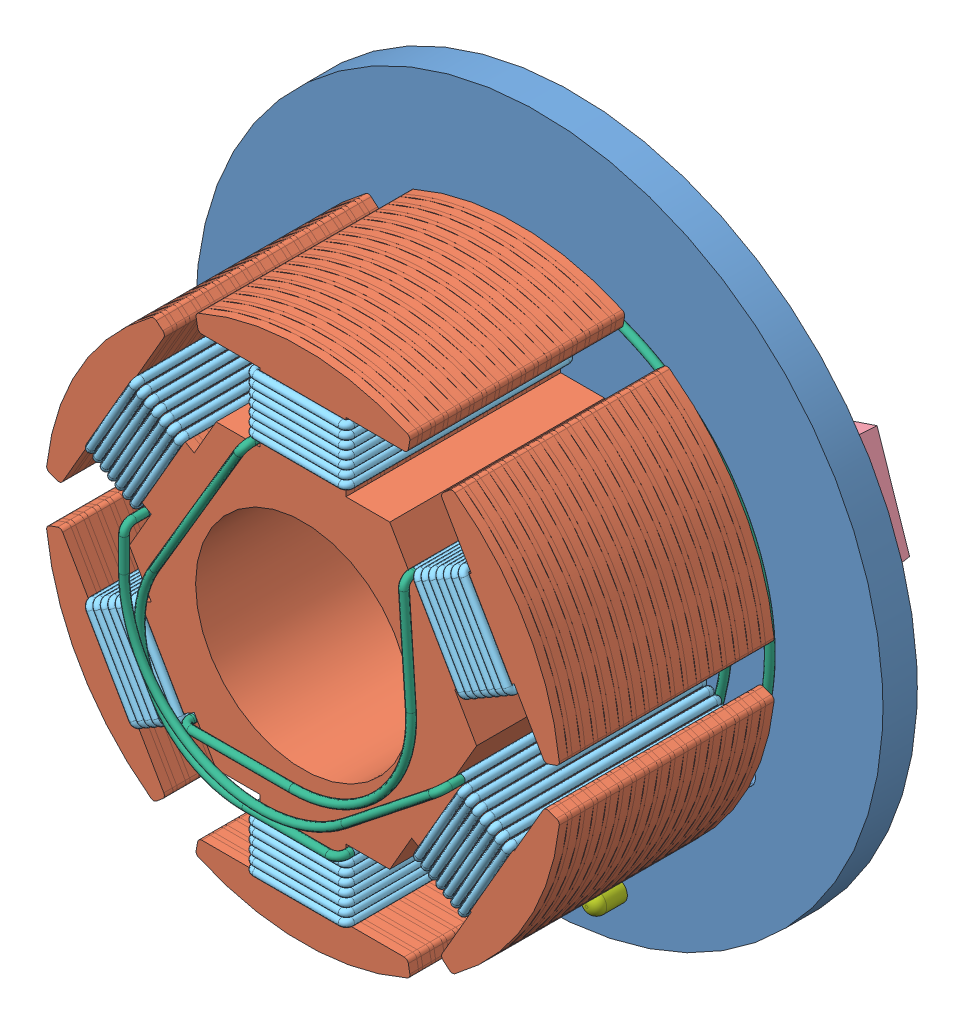
SolidWorks assembly Brushless motor, configuration Predeterminado. Lengths in mm.
Overall size (16 16 8.48).
12 component instances, 7 part files, 21 mates.
Components (placement in the parent):
- Board-1: Board [Predeterminado] at origin size (16 16 0.8)
- Stator-1: Stator [Predeterminado] at (0 0 3.55) size (11.93 12 5.5)
- Hall Effect sensor-1: Hall Effect sensor [WE] at (-5.3023 -0.9391 0) x (-0.233503 0.972356 0) z (-0.972356 -0.233503 0) size (6.3 1.6 2.6)
- Controller-1: Controller [Predeterminado] at (5.1574 2.3195 0) x (0.319288 -0.947658 0) z (0.947658 0.319288 0) size (4.81 0.99 3)
- Coil-1: Coil [Predeterminado] at (0 -5.01 1.29) x (-1 0 0) z (0 1 0) size (2.38 5.38 1.58)
- Pieza2^Brushless motor-1: Pieza2^Brushless motor [Predeterminado] at origin size (10.72 12.51 6.88) (virtual)
- Pieza3^Brushless motor-1: Pieza3^Brushless motor [Predeterminado] at (0 0 0.8) size (4.1 0.74 1.7) (virtual)
- Coil-2: Coil [Predeterminado] at (-4.3388 -2.505 1.29) x (-0.5 0.866025 0) z (0.866025 0.5 0) size (2.38 5.38 1.58)
- Coil-3: Coil [Predeterminado] at (-4.3388 2.505 1.29) x (0.5 0.866025 0) z (0.866025 -0.5 0) size (2.38 5.38 1.58)
- Coil-4: Coil [Predeterminado] at (0 5.01 1.29) x (1 0 0) z (0 -1 0) size (2.38 5.38 1.58)
- Coil-5: Coil [Predeterminado] at (4.3388 2.505 1.29) x (0.5 -0.866025 0) z (-0.866025 -0.5 0) size (2.38 5.38 1.58)
- Coil-6: Coil [Predeterminado] at (4.3388 -2.505 1.29) x (-0.5 -0.866025 0) z (-0.866025 0.5 0) size (2.38 5.38 1.58)
Mates (geometry in assembly coordinates):
- Coincidente1: coincident aligned: plane of Board-1 through (0 0 0) normal (0 0 1)
- Coincidente2: coincident aligned: plane of Board-1 through (0 0 0) normal (0 1 0)
- Coincidente3: coincident aligned: plane of Board-1 through (0 0 0) normal (1 0 0)
- Coincidente4: coincident anti-aligned: plane of Board-1 through (0 0 0.8) normal (0 0 1); plane of Stator-1 through (0 0 0.8) normal (0 0 -1)
- Concéntrica1: concentric aligned: cylinder of Board-1 through (0 0 0.8) axis (0 0 -1) radius 2.5; cylinder of Stator-1 through (0 0 6.3) axis (0 0 -1) radius 2.5
- Bloquear1: lock: unknown of Board-1; unknown of Hall Effect sensor-1
- Coincidente16: coincident anti-aligned: plane of Board-1 through (0 0 0) normal (0 0 -1); plane of Controller-1 through (5.1574 2.3195 0) normal (0 0 1)
- Bloquear2: lock: unknown of Board-1; unknown of Controller-1
- Coincidente17: coincident anti-aligned: plane of Coil-1 through (0 -5.01 1.29) normal (-1 0 0)
- Tangente1: tangent anti-aligned: plane of Stator-1 through (0 0 6.3) normal (0 0 1); cylinder of Coil-1 through (1 -5.01 6.39) axis (-1 0 0) radius 0.09
- Paralelo1: parallel aligned: plane of Coil-1 through (0 -5.01 1.29) normal (0 0 1)
- Tangente2: tangent anti-aligned: plane of Stator-1 through (2.3536 -5.1 6.1) normal (0 1 0); cylinder of Coil-1 through (1.1 -5.01 3.79) axis (0 0 1) radius 0.09
- Bloquear3: lock: unknown of Board-1; unknown of Coil-1
- EnPosición1: in place: plane of ? through (0 0 0) normal (0 0 1); moOrthogonalPlaneRef_w of ? through (0 0 0) normal (0 1 0); plane of ? through (0 0 0) normal (1 0 0); unknown of ?
- Coincidente18: coincident aligned: 
- Coincidente19: coincident aligned: plane of Pieza2^Brushless motor-1 through (0 0 0) normal (0 1 0)
- Coincidente20: coincident anti-aligned: plane of Pieza2^Brushless motor-1 through (0 0 0) normal (1 0 0)
- EnPosición2: in place: plane of ? through (0 0 0.8) normal (0 0 1); plane of Pieza3^Brushless motor-1 through (0 0 0.8) normal (0 0 1); plane of ? through (0 0 0.8) normal (0 0 1); plane of Pieza3^Brushless motor-1 through (0 0 0.8) normal (0 1 0); plane of ? through (0 0 0.8) normal (0 0 1); plane of Pieza3^Brushless motor-1 through (0 0 0.8) normal (1 0 0); plane of ? through (0 0 0.8) normal (0 0 1); unknown of Pieza3^Brushless motor-1
- Coincidente21: coincident aligned: plane of Board-1; plane of Pieza3^Brushless motor-1
- Coincidente22: coincident aligned: moOrthogonalPlaneRef_w of Board-1 through (0 0 0.8) normal (0 1 0); plane of Pieza3^Brushless motor-1 through (0 0 0.8) normal (0 1 0)
- Coincidente23: coincident anti-aligned: moOrthogonalPlaneRef_w of Board-1 through (0 0 0.8) normal (-1 0 0); plane of Pieza3^Brushless motor-1 through (0 0 0.8) normal (1 0 0)
